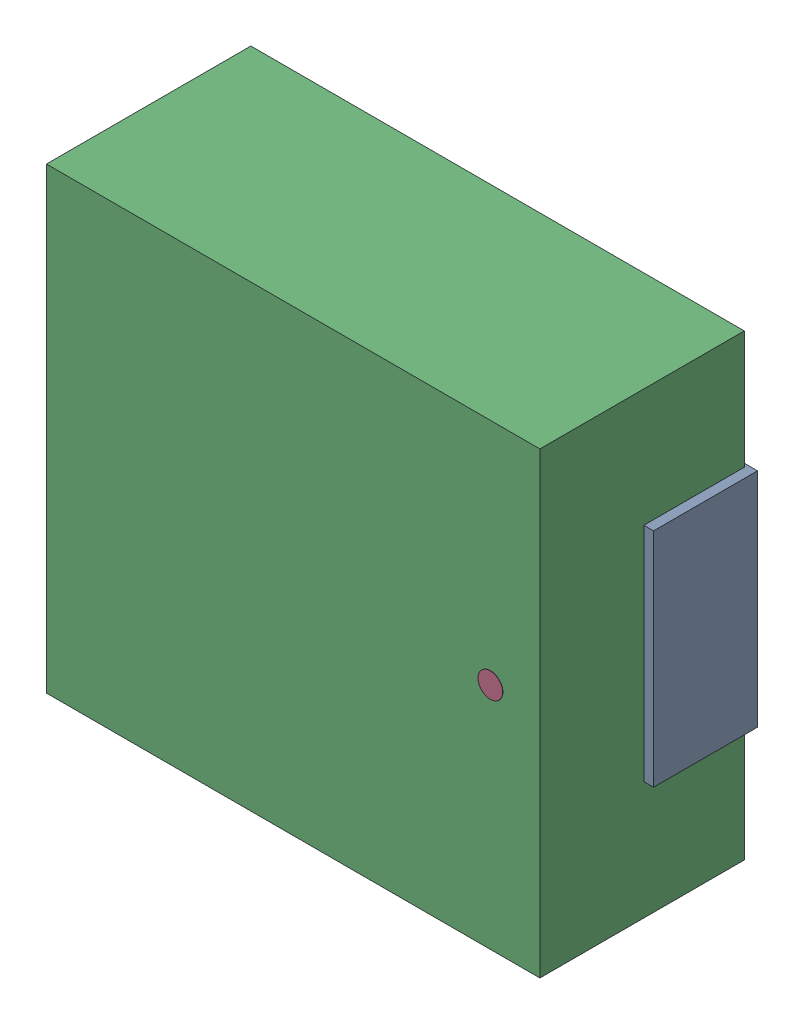
SolidWorks assembly L2, configuration Standard. Lengths in mm.
Overall size (7.39 6.6 3).
5 component instances, 4 part files, 0 mates.
Components (placement in the parent):
- L2-subassembly-1-1: L2-subassembly-1 [Standard] at (-4.6001 -12.7001 0) x (-1 0 0) z (0 0 1) size (7.39 6.6 3)
  - IND_AMDLA7030Q_7P1X6P6_ABR-1: IND_AMDLA7030Q_7P1X6P6_ABR [Standard] at origin size (1.91 3.2 1.5)
  - IND_AMDLA7030Q_7P1X6P6_ABR-1-1: IND_AMDLA7030Q_7P1X6P6_ABR-1 [Standard] at origin size (1.91 3.2 1.5)
  - IND_AMDLA7030Q_7P1X6P6_ABR-2-1: IND_AMDLA7030Q_7P1X6P6_ABR-2 [Standard] at origin size (7.11 6.6 2.95)
  - IND_AMDLA7030Q_7P1X6P6_ABR-3-1: IND_AMDLA7030Q_7P1X6P6_ABR-3 [Standard] at origin size (0.36 0.36 0.01)
